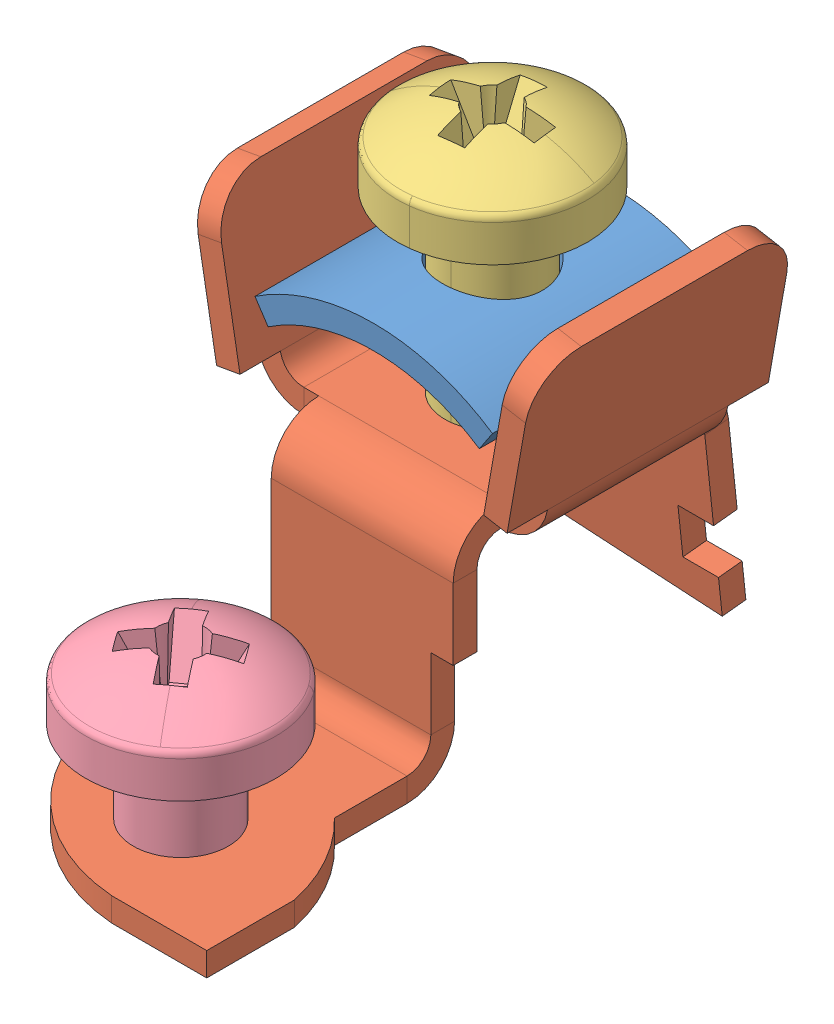
SolidWorks assembly AL-ML-123076 Разъем заземления, configuration По умолчанию. Lengths in mm.
Overall size (14.48 22.09 26.77).
4 component instances, 4 part files, 4 mates.
Components (placement in the parent):
- AL-ML-122076 Прижимная пластина-1: AL-ML-122076 Прижимная пластина [По умолчанию] at origin size (10 2.35 10)
- AL-ML-123076 Разъем заземления-1: AL-ML-123076 Разъем заземления [По умолчанию] at (0 3.9986 0) x (0 0 -1) z (1 0 0) size (25.45 17.2 14.48)
- Винт ISO7045 М4х10-1: Винт ISO7045 М4х10 [По умолчанию] at (-30.0506 -43.1274 -27.7779) x (0 -1 0) z (0.118311 0 0.992977) size (13.1 8 8)
- Винт ISO7045 М4х6-1: Винт ISO7045 М4х6 [По умолчанию] at (0.2912 4.8093 12.2017) x (0 -1 0) z (-0.81102 0 0.585018) size (9.1 8 8)
Mates (geometry in assembly coordinates):
- Концентричный1: concentric anti-aligned: cylinder of AL-ML-122076 Прижимная пластина-1 through (0 6.6518 0) axis (0 -1 0) radius 2.1; cylinder of AL-ML-123076 Разъем заземления-1 through (0 -6.0516 0) axis (0 1 0) radius 1.65
- Параллельность1: parallel anti-aligned: line of AL-ML-122076 Прижимная пластина-1 through (5 7.4833 5) axis (0 0 -1); line of AL-ML-123076 Разъем заземления-1 through (7.2383 11.0239 -3.5) axis (0 0 1)
- Концентричный2: concentric aligned: cylinder of AL-ML-123076 Разъем заземления-1 through (0 -6.0516 0) axis (0 1 0) radius 1.65; cylinder of Винт ISO7045 М4х10-1 through (0 39.9595 0) axis (0 1 0) radius 2
- Концентричный3: concentric aligned: cylinder of AL-ML-123076 Разъем заземления-1 through (0 -6.0516 13.12) axis (0 1 0) radius 1.65; cylinder of Винт ISO7045 М4х6-1 through (0 26.9676 13.12) axis (0 1 0) radius 2
